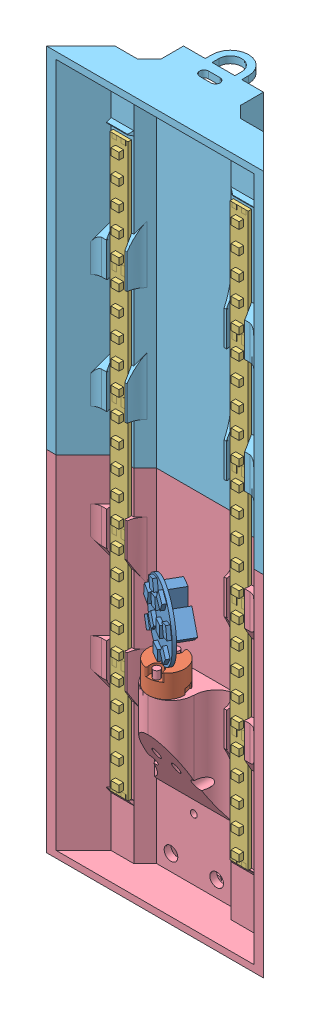
SolidWorks assembly Center-Decke, configuration Standard. Lengths in mm.
Overall size (95 306 46.66).
6 component instances, 5 part files, 15 mates.
Components (placement in the parent):
- G4 LED-1: G4 LED [Standard] at (-69.7688 71.9428 102.8196) x (-0.866025 0 -0.5) z (0 1 0) size (30 9.9 34.79)
- G4 Sockel-1: G4 Sockel [Standard] at (-69.3938 46.9428 102.1701) x (0.258819 0 0.965926) z (0 1 0) size (16 16 33.5)
- LED-Bar-1: LED-Bar [Standard] at (-39.0865 238.9428 95.1701) x (0 1 0) z (1 0 0) size (250 3.5 8)
- LED-Bar-2: LED-Bar [Standard] at (-91.7012 238.9428 95.1701) x (0 1 0) z (1 0 0) size (250 3.5 8)
- Center-Decke-Gehäuse-Left-1: Center-Decke-Gehäuse-Left [Standard] at (-69.3938 -38.0572 77.1701) size (95 157.8 44)
- Center-Decke-Gehäuse-Right-1: Center-Decke-Gehäuse-Right [Standard] at (-69.3938 267.9428 77.1701) x (-1 0 0) z (0 0 1) size (95 153 41)
Mates (geometry in assembly coordinates):
- Deckungsgleich1: coincident anti-aligned: plane of LED-Bar-1 through (-39.0865 238.9428 95.1701) normal (0 0 -1); plane of Center-Decke-Gehäuse-Left-1 through (-48.1365 114.9428 95.1701) normal (0 0 1)
- Deckungsgleich2: coincident anti-aligned: plane of LED-Bar-2 through (-91.7012 238.9428 95.1701) normal (0 0 -1); plane of Center-Decke-Gehäuse-Left-1 through (-90.6512 114.9428 95.1701) normal (0 0 1)
- Deckungsgleich7: coincident anti-aligned: plane of G4 Sockel-1 through (-69.3938 46.9428 102.1701) normal (0 -1 0); plane of Center-Decke-Gehäuse-Left-1 through (-79.3938 46.9428 110.1701) normal (0 1 0)
- Konzentrisch1: concentric: cylinder of G4 Sockel-1 through (-70.9468 46.9428 96.3745) axis (0 1 0) radius 1.5; cylinder of Center-Decke-Gehäuse-Left-1 through (-70.9468 56.9428 96.3745) axis (0 -1 0) radius 1.5
- Konzentrisch2: concentric: cylinder of G4 Sockel-1 through (-67.8409 46.9428 107.9656) axis (0 1 0) radius 1.5; cylinder of Center-Decke-Gehäuse-Left-1 through (-67.8409 56.9428 107.9656) axis (0 -1 0) radius 1.5
- Konzentrisch3: concentric anti-aligned: cylinder of G4 Sockel-1 through (-67.2288 46.9428 103.4201) axis (0 1 0) radius 0.75; cylinder of G4 LED-1 through (-67.2288 59.6577 103.4201) axis (0 -1 0) radius 0.75
- Konzentrisch4: concentric: cylinder of G4 LED-1 through (-71.5589 59.6577 100.9201) axis (0 -1 0) radius 0.75; cylinder of G4 Sockel-1 through (-71.5589 46.9428 100.9201) axis (0 1 0) radius 0.75
- Tangential2: tangent: cylinder of G4 LED-1 through (-70.4688 71.9428 104.032) axis (0.5 0 -0.866025) radius 15; plane of G4 Sockel-1 through (-69.3938 56.9428 102.1701) normal (0 1 0)
- Deckungsgleich8: coincident: plane of Center-Decke-Gehäuse-Left-1 through (-69.3938 114.9428 77.1701) normal (0 1 0); plane of Center-Decke-Gehäuse-Right-1 through (-69.3938 114.9428 77.1701) normal (0 -1 0)
- Deckungsgleich9: coincident: line of Center-Decke-Gehäuse-Left-1 through (-101.8938 114.9428 92.1701) axis (-0.707107 0 0.707107); line of Center-Decke-Gehäuse-Right-1 through (-107.7015 114.9428 97.9777) axis (0.707107 0 -0.707107)
- Deckungsgleich10: coincident anti-aligned: line of Center-Decke-Gehäuse-Left-1 through (-30.9448 114.9428 98.1191) axis (-0.707107 0 -0.707107); line of Center-Decke-Gehäuse-Right-1 through (-36.8938 114.9428 92.1701) axis (0.707107 0 0.707107)
- Deckungsgleich11: coincident anti-aligned: plane of LED-Bar-2 through (-99.7012 238.9428 96.6701) normal (-1 0 0); plane of Center-Decke-Gehäuse-Left-1 through (-99.7012 31.4428 98.1701) normal (1 0 0)
- Deckungsgleich12: coincident anti-aligned: plane of LED-Bar-1 through (-39.0865 238.9428 96.6701) normal (1 0 0); plane of Center-Decke-Gehäuse-Left-1 through (-39.0865 31.4428 98.1701) normal (-1 0 0)
- Deckungsgleich13: coincident anti-aligned: plane of LED-Bar-1 through (-39.0865 -11.0572 96.6701) normal (0 -1 0); plane of Center-Decke-Gehäuse-Left-1 through (-48.1365 -11.0572 96.1701) normal (0 1 0)
- Deckungsgleich14: coincident anti-aligned: plane of LED-Bar-2 through (-91.7012 -11.0572 96.6701) normal (0 -1 0); plane of Center-Decke-Gehäuse-Left-1 through (-90.6512 -11.0572 96.1701) normal (0 1 0)
